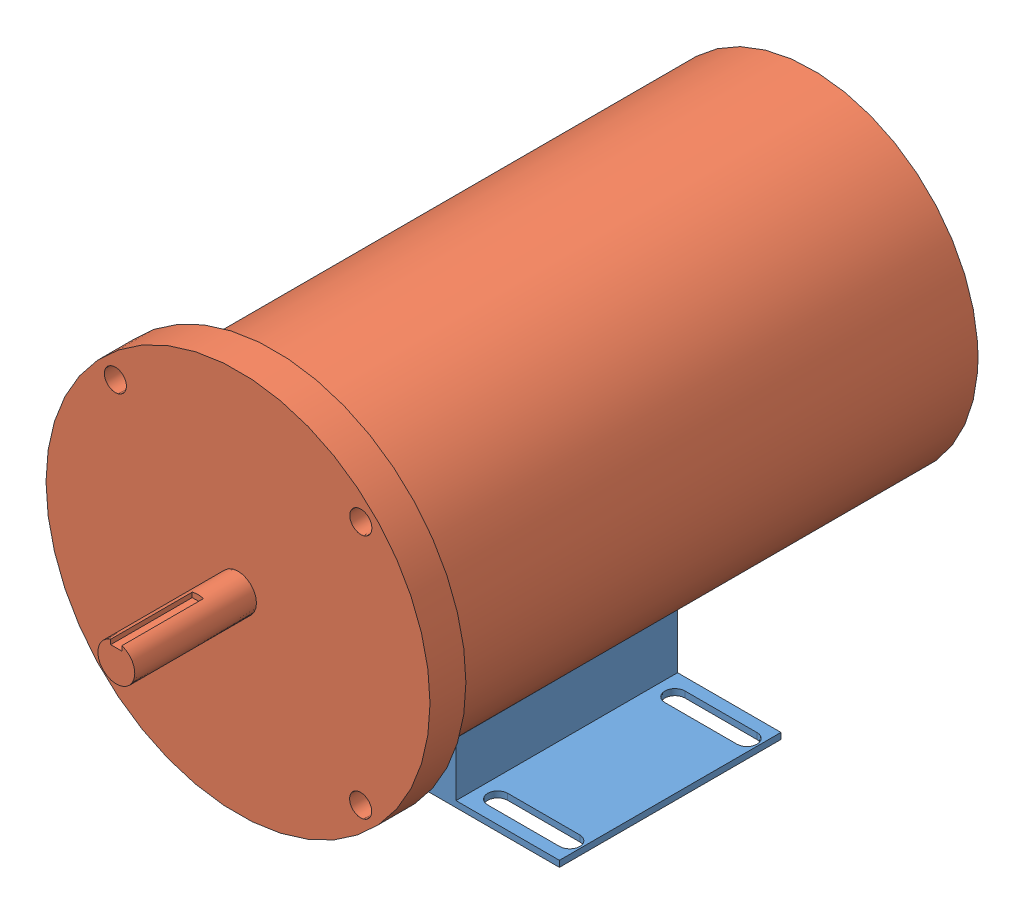
SolidWorks assembly MotorAss, configuration Default. Lengths in mm.
Overall size (165.1 171.45 298.96).
2 component instances, 2 part files, 2 mates.
Components (placement in the parent):
- motorMount-1: motorMount [Default] at origin size (165.1 28.4 95.25)
- motor-1: motor [Default] at (0 87.5792 -95.758) size (165.1 165.1 298.96)
Mates (geometry in assembly coordinates):
- Concentric1: concentric: cylinder of motorMount-1 through (0 87.5792 95.25) axis (0 0 -1) radius 71.501; cylinder of motor-1 through (0 87.5792 193.9531) axis (0 0 -1) radius 71.501
- Distance2: distance = 55.626 mm: plane of motorMount-1 through (0 87.5792 95.25) normal (0 0 1); plane of motor-1 through (0 87.5792 150.876) normal (0 0 1)
